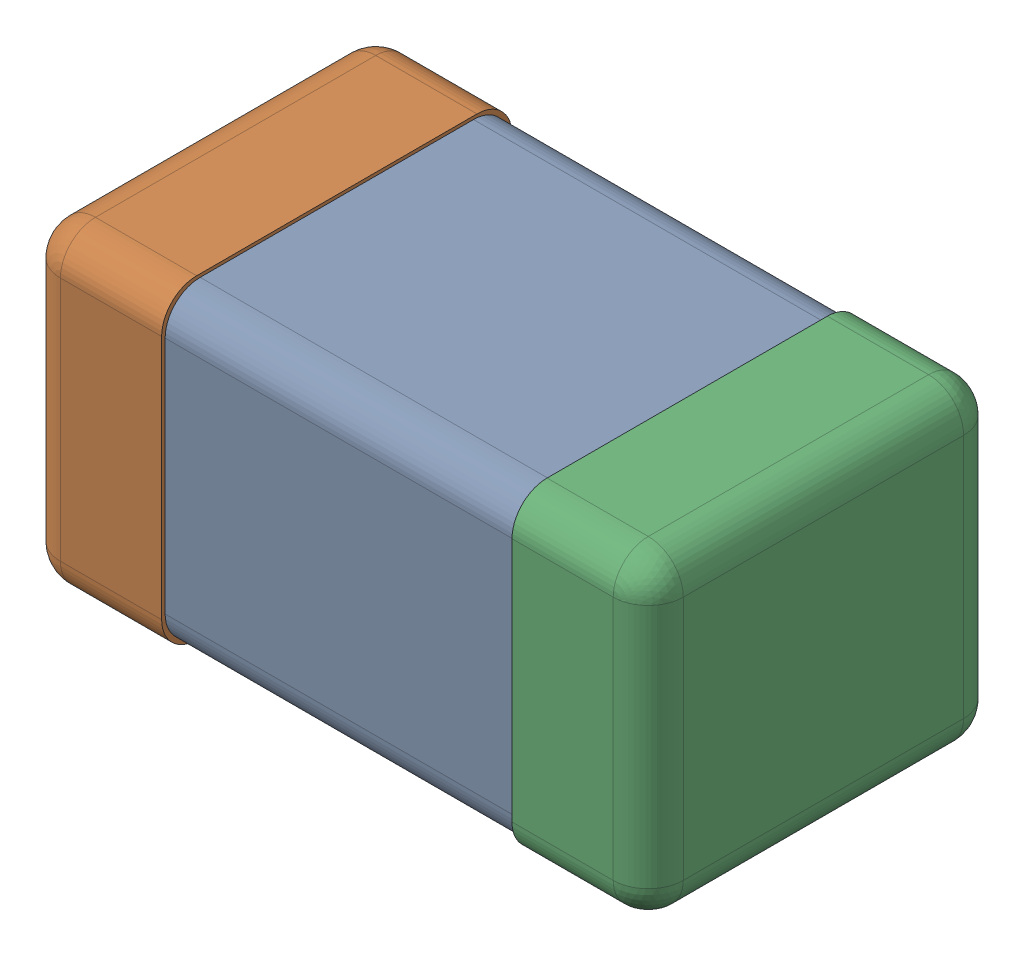
SolidWorks assembly C2, configuration Predeterminado. Lengths in mm.
Overall size (1.6 0.81 0.9).
4 component instances, 3 part files, 0 mates.
Components (placement in the parent):
- 6074694320-1: 6074694320 [Predeterminado] at (28.5 43.5 0) x (-1 0 0) z (0 0 1) size (1.6 0.81 0.9)
  - body2-1-1: body2-1 [Predeterminado] at origin size (0.9 0.79 0.88)
  - Fillet2-1-1: Fillet2-1 [Predeterminado] at origin size (0.35 0.81 0.9)
  - Fillet1-1-1: Fillet1-1 [Predeterminado] at origin size (0.35 0.81 0.9)
